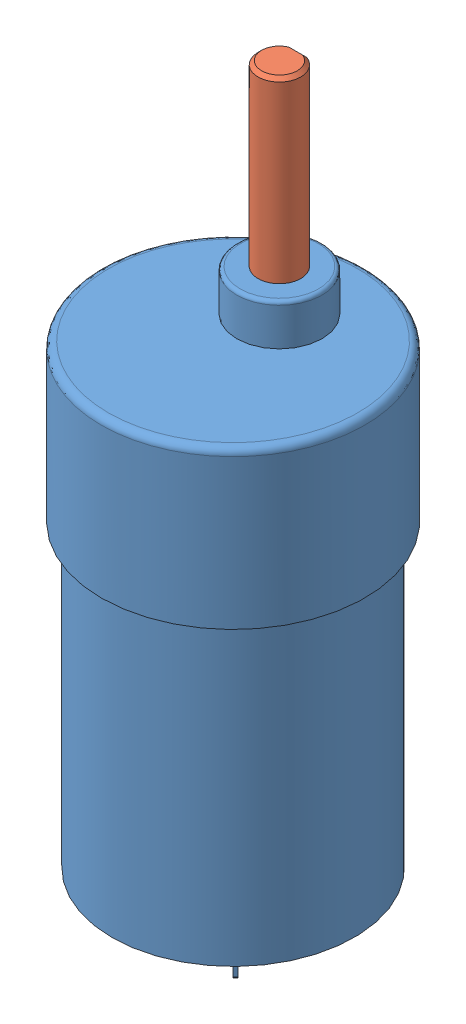
SolidWorks assembly tetrix_739083, configuration Default. Lengths in mm.
Overall size (37 98.8 37).
2 component instances, 2 part files, 2 mates.
Components (placement in the parent):
- tetrix_739083_motor-1: tetrix_739083_motor [Default] at origin size (37 73.8 37)
- tetrix_739083_axle-1: tetrix_739083_axle [Default] at (0 27.8 -6.5) size (6 25 5.8)
Mates (geometry in assembly coordinates):
- Coincident1: coincident: plane of tetrix_739083_motor-1 through (0 27.8 -6.5) normal (0 1 0); plane of tetrix_739083_axle-1 through (0 27.8 -6.5) normal (0 -1 0)
- Concentric1: concentric aligned: cylinder of tetrix_739083_motor-1 through (0 22 -6.5) axis (0 1 0) radius 6; cylinder of tetrix_739083_axle-1 through (0 27.8 -6.5) axis (0 1 0) radius 3
